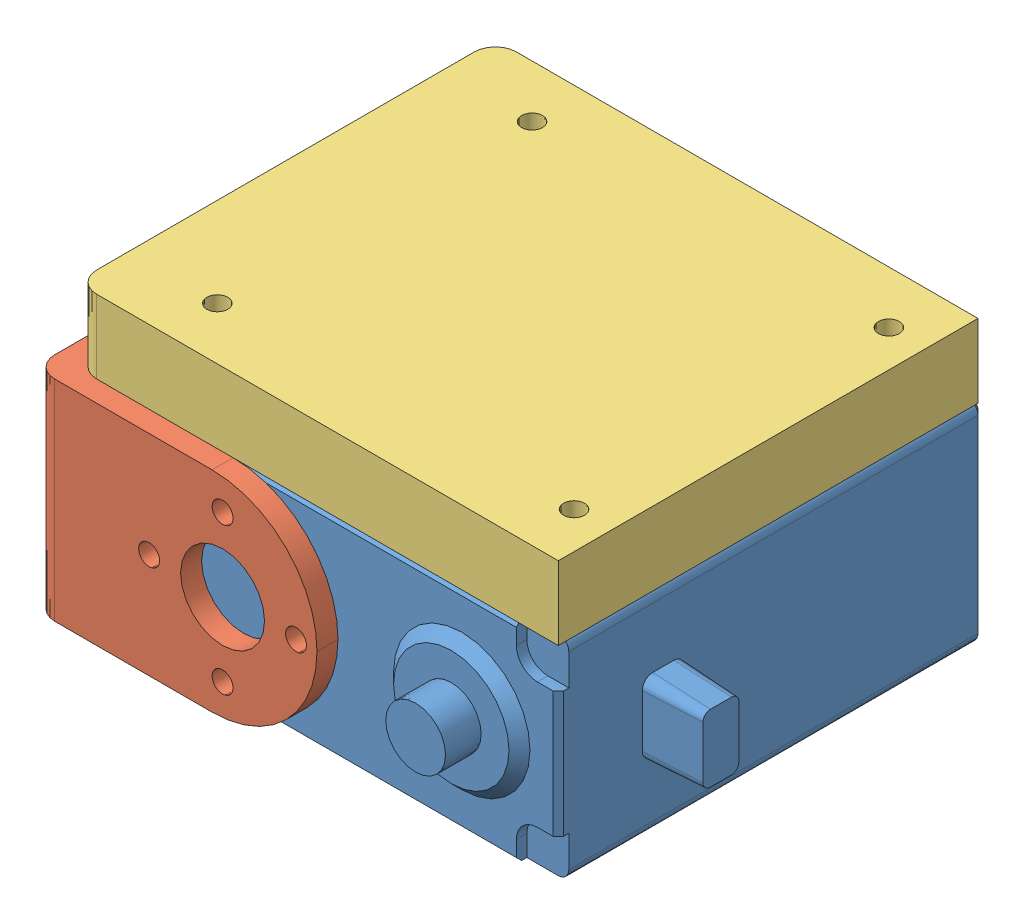
SolidWorks assembly moteur-complet, configuration Défaut. Lengths in mm.
Overall size (55.5 27 48.8).
11 component instances, 5 part files, 26 mates.
Components (placement in the parent):
- moteur-1: moteur [Défaut] at (-9.5825 -1.0731 48.8) size (45.5 20 48.8)
- moteur-support-fixe-1: moteur-support-fixe [Défaut] at (-5.7196 9.1116 15.94) x (1 0 0) z (0 -1 0) size (27.58 44 20)
- moteur_semelle-1: moteur_semelle [Défaut] at (-31.3007 -10.8884 28.8) x (-1 0 0) z (0 0 1) size (48 27 40)
- ecrou-h-1: ecrou-h [6007 HU M2] at (-27.7007 -5.8884 23.8) x (0 0.5 -0.866025) z (0 -0.866025 -0.5) size (4 1.6 4.62)
- ecrou-h-2: ecrou-h [6007 HU M2] at (-27.7007 -5.8884 33.8) x (0 -0.5 -0.866025) z (0 -0.866025 0.5) size (4 1.6 4.62)
- ecrou-h-3: ecrou-h [6007 HU M2] at (-27.7007 4.1116 33.8) x (0 -0.5 -0.866025) z (0 -0.866025 0.5) size (4 1.6 4.62)
- ecrou-h-4: ecrou-h [6007 HU M2] at (-27.7007 4.1116 23.8) x (0 -1 0) z (0 0 1) size (4 1.6 4.62)
- vis-chc-1: vis-chc [Vis CHC M2x6] at (-33.3007 -5.8884 33.8) x (0 -0.454411 0.890792) z (0 -0.890792 -0.454411) size (3.8 8 3.8)
- vis-chc-2: vis-chc [Vis CHC M2x6] at (-33.3007 4.1116 33.8) x (0 -0.381849 0.924225) z (0 -0.924225 -0.381849) size (3.8 8 3.8)
- vis-chc-3: vis-chc [Vis CHC M2x6] at (-33.3007 4.1116 23.8) x (0 -0.381849 0.924225) z (0 -0.924225 -0.381849) size (3.8 8 3.8)
- vis-chc-4: vis-chc [Vis CHC M2x6] at (-33.3007 -5.8884 23.8) x (0 -0.381849 0.924225) z (0 -0.924225 -0.381849) size (3.8 8 3.8)
Mates (geometry in assembly coordinates):
- Coaxiale12: concentric aligned: cylinder of moteur-1 through (-22.3007 -0.8884 43.8) axis (0 0 1) radius 0.79; cylinder of moteur-support-fixe-1 through (-22.3007 -0.8884 6.799) axis (0 0 1) radius 1
- Coaxiale13: concentric aligned: cylinder of moteur-1 through (-15.3007 -7.8884 43.8) axis (0 0 1) radius 0.79; cylinder of moteur-support-fixe-1 through (-15.3007 -7.8884 6.799) axis (0 0 1) radius 1
- Coïncidente2: coincident anti-aligned: plane of moteur-1 through (-9.5825 -1.0731 48.8) normal (0 0 1); plane of moteur-support-fixe-1 through (-29.3007 -10.8884 48.8) normal (0 0 -1)
- Coïncidente3: coincident anti-aligned: plane of moteur-support-fixe-1 through (-31.3007 -10.8884 10.8) normal (1 0 0); plane of moteur_semelle-1 through (-31.3007 16.1116 8.8) normal (-1 0 0)
- Coïncidente5: coincident anti-aligned: plane of moteur-1 through (-25.3007 9.1116 8.3) normal (0 1 0); plane of moteur_semelle-1 through (14.6993 9.1116 48.8) normal (0 -1 0)
- Coaxiale14: concentric anti-aligned: cylinder of moteur-support-fixe-1 through (-5.7186 -0.8884 28.8) axis (-1 0 0) radius 3; cylinder of moteur_semelle-1 through (-33.3007 -0.8884 28.8) axis (1 0 0) radius 2.9
- Coaxiale15: concentric anti-aligned: cylinder of moteur_semelle-1 through (14.7003 -5.8884 23.8) axis (-1 0 0) radius 1.1; cylinder of ecrou-h-m2-1 through (-29.3007 -5.8884 23.8) axis (1 0 0) radius 0.7835
- Parallèle2: parallel anti-aligned: plane of moteur_semelle-1 through (-29.3007 -8.0535 25.05) normal (0 1 0); plane of ecrou-h-m2-1 through (-29.3007 -7.8884 24.9547) normal (0 -1 0)
- Coïncidente9: coincident anti-aligned: plane of moteur_semelle-1 through (-29.3007 -10.8884 28.8) normal (1 0 0); plane of ecrou-h-m2-1 through (-29.3007 -3.8884 22.6453) normal (-1 0 0)
- Coaxiale16: concentric anti-aligned: cylinder of moteur_semelle-1 through (14.7003 4.1116 33.8) axis (-1 0 0) radius 1.1; cylinder of ecrou-h-m2-3 through (-29.3007 4.1116 33.8) axis (1 0 0) radius 0.7835
- Coaxiale17: concentric anti-aligned: cylinder of moteur_semelle-1 through (14.7003 4.1116 23.8) axis (-1 0 0) radius 1.1; cylinder of ecrou-h-m2-4 through (-29.3007 4.1116 23.8) axis (1 0 0) radius 0.7835
- Coaxiale18: concentric anti-aligned: cylinder of moteur_semelle-1 through (14.7003 -5.8884 33.8) axis (-1 0 0) radius 1.1; cylinder of ecrou-h-m2-2 through (-29.3007 -5.8884 33.8) axis (1 0 0) radius 0.7835
- Parallèle3: parallel anti-aligned: plane of moteur_semelle-1 through (-29.3007 -8.0535 35.05) normal (0 1 0); plane of ecrou-h-m2-2 through (-29.3007 -7.8884 34.9547) normal (0 -1 0)
- Coïncidente11: coincident anti-aligned: plane of moteur_semelle-1 through (-29.3007 -10.8884 28.8) normal (1 0 0); plane of ecrou-h-m2-2 through (-29.3007 -5.8884 31.4906) normal (-1 0 0)
- Parallèle4: parallel anti-aligned: plane of moteur_semelle-1 through (-29.3007 1.9465 25.05) normal (0 1 0); plane of ecrou-h-m2-4 through (-29.3007 2.1116 24.9547) normal (0 -1 0)
- Coïncidente13: coincident anti-aligned: plane of moteur_semelle-1 through (-29.3007 -10.8884 28.8) normal (1 0 0); plane of ecrou-h-m2-4 through (-29.3007 2.1116 22.6453) normal (-1 0 0)
- Parallèle5: parallel anti-aligned: plane of moteur_semelle-1 through (-29.3007 1.9465 35.05) normal (0 1 0); plane of ecrou-h-m2-3 through (-29.3007 2.1116 34.9547) normal (0 -1 0)
- Coïncidente15: coincident anti-aligned: plane of moteur_semelle-1 through (-29.3007 -10.8884 28.8) normal (1 0 0); plane of ecrou-h-m2-3 through (-29.3007 4.1116 31.4906) normal (-1 0 0)
- Coaxiale20: concentric aligned: cylinder of moteur-support-fixe-1 through (-5.7186 -5.8884 33.8) axis (-1 0 0) radius 1.5; cylinder of vis-chc-m2x5-1 through (-27.3007 -5.8884 33.8) axis (-1 0 0) radius 1
- Coaxiale21: concentric aligned: cylinder of moteur-support-fixe-1 through (-5.7186 -5.8884 23.8) axis (-1 0 0) radius 1.5; cylinder of vis-chc-m2x5-4 through (-27.3007 -5.8884 23.8) axis (-1 0 0) radius 1
- Coaxiale22: concentric aligned: cylinder of moteur-support-fixe-1 through (-5.7186 4.1116 23.8) axis (-1 0 0) radius 1.5; cylinder of vis-chc-m2x5-3 through (-27.3007 4.1116 23.8) axis (-1 0 0) radius 1
- Coaxiale23: concentric aligned: cylinder of moteur-support-fixe-1 through (-5.7186 4.1116 33.8) axis (-1 0 0) radius 1.5; cylinder of vis-chc-m2x5-2 through (-27.3007 4.1116 33.8) axis (-1 0 0) radius 1
- Coïncidente18: coincident anti-aligned: plane of moteur-support-fixe-1 through (-33.3007 -10.8884 48.8) normal (-1 0 0); plane of vis-chc-m2x5-2 through (-33.3007 4.1116 33.8) normal (1 0 0)
- Coïncidente19: coincident anti-aligned: plane of moteur-support-fixe-1 through (-33.3007 -10.8884 48.8) normal (-1 0 0); plane of vis-chc-m2x5-3 through (-33.3007 4.1116 23.8) normal (1 0 0)
- Coïncidente20: coincident anti-aligned: plane of moteur-support-fixe-1 through (-33.3007 -10.8884 48.8) normal (-1 0 0); plane of vis-chc-m2x5-1 through (-33.3007 -5.8884 33.8) normal (1 0 0)
- Coïncidente21: coincident anti-aligned: plane of moteur-support-fixe-1 through (-33.3007 -10.8884 48.8) normal (-1 0 0); plane of vis-chc-m2x5-4 through (-33.3007 -5.8884 23.8) normal (1 0 0)
